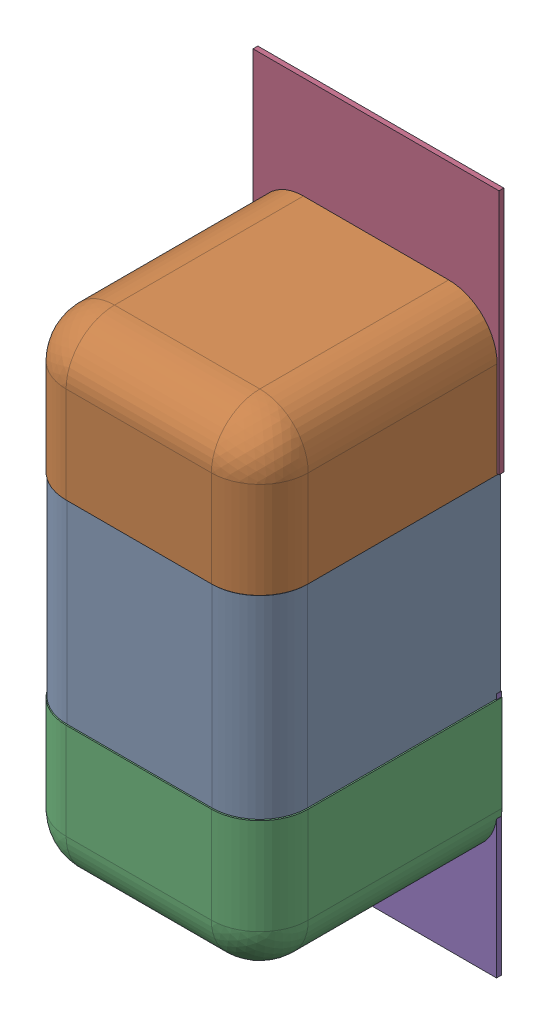
SolidWorks assembly C25, configuration Défaut. Lengths in mm.
Overall size (0.51 1.41 0.5).
8 component instances, 4 part files, 0 mates.
Components (placement in the parent):
- 6501210464-1: 6501210464 [Défaut] at (40.4622 -21.4068 0) x (0 -1 0) z (-1 0 0) size (1 0.5 0.5)
  - Open CASCADE STEP translator 7.5 2.33.1.1-1: Open CASCADE STEP translator 7.5 2.33.1.1 [Défaut] at origin size (0.4 0.5 0.5)
  - Open CASCADE STEP translator 7.5 2.33.1.2-1: Open CASCADE STEP translator 7.5 2.33.1.2 [Défaut] at origin size (0.3 0.5 0.5)
  - Open CASCADE STEP translator 7.5 2.33.1.3-1: Open CASCADE STEP translator 7.5 2.33.1.3 [Défaut] at origin size (0.3 0.5 0.5)
- 6504207776-1: 6504207776 [Défaut] at (40.4622 -20.9495 0) size (0.51 0.51 0.01)
  - Extruded-1: Extruded [Défaut] at origin size (0.51 0.51 0.01)
- 6504207776-2: 6504207776 [Défaut] at (40.457 -21.8518 0) size (0.51 0.51 0.01)
  - Extruded-1: Extruded [Défaut] at origin size (0.51 0.51 0.01)
